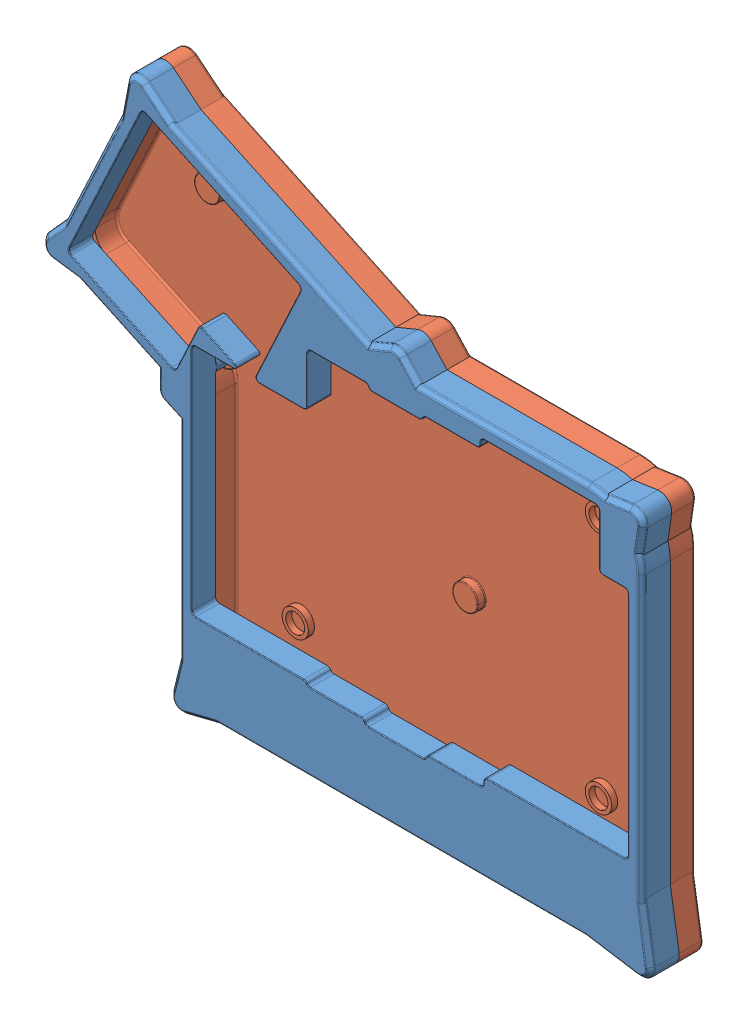
SolidWorks assembly LeftHand, configuration Default. Lengths in mm.
Overall size (279.37 254.04 17.85).
2 component instances, 2 part files, 9 mates.
Components (placement in the parent):
- TopLeftCase-1: TopLeftCase [Default] at (-21.2682 -149.7269 -2.413) x (0.923728 -0.383049 0) z (0 0 1) size (227.52 180.67 11.97)
- FlatLeftCase-1: FlatLeftCase [Default] at origin size (200.82 175.03 9.11)
Mates (geometry in assembly coordinates):
- Coïncidente1: coincident aligned: plane of TopLeftCase-1 through (-71.628 -108.2929 9.5) normal (-1 0 0); plane of Double_BottomLeftCase2-1 through (-71.628 -32.6786 -6.4725) normal (-1 0 0)
- Coïncidente2: coincident aligned: plane of TopLeftCase-1 through (-62.103 -117.8179 9.5) normal (0 -1 0); plane of Double_BottomLeftCase2-1 through (12.105 -117.8179 -6.4725) normal (0 -1 0)
- Coïncidente3: coincident anti-aligned: plane of Double_BottomLeftCase2-1 through (-77.47 -32.6786 0) normal (0 0 1); plane of TopLeftCase-1 through (-62.103 -108.2929 0) normal (0 0 -1)
- Coïncidente4: coincident aligned: plane of TopLeftCase-1 through (-71.628 -108.2929 9.5) normal (-1 0 0); plane of Single_BottomLeftCase-1 through (-71.628 -32.6786 -6.4725) normal (-1 0 0)
- Coïncidente5: coincident aligned: plane of Double_BottomLeftCase2-1 through (12.105 -117.8179 -6.4725) normal (0 -1 0); plane of Single_BottomLeftCase-1 through (12.105 -117.8179 -6.4725) normal (0 -1 0)
- Coïncidente6: coincident anti-aligned: plane of TopLeftCase-1 through (-62.103 -108.2929 0) normal (0 0 -1); plane of Single_BottomLeftCase-1 through (-77.47 -32.6786 0) normal (0 0 1)
- Coïncidente7: coincident aligned: plane of TopLeftCase-1 through (-71.628 -108.2929 9.5) normal (-1 0 0); plane of FlatLeftCase-1 through (-71.628 -32.6786 -6.4725) normal (-1 0 0)
- Coïncidente8: coincident aligned: plane of TopLeftCase-1 through (-62.103 -117.8179 9.5) normal (0 -1 0); plane of FlatLeftCase-1 through (12.105 -117.8179 -6.4725) normal (0 -1 0)
- Coïncidente9: coincident anti-aligned: plane of TopLeftCase-1 through (-62.103 -108.2929 0) normal (0 0 -1); plane of FlatLeftCase-1 through (-77.47 -32.6786 0) normal (0 0 1)
